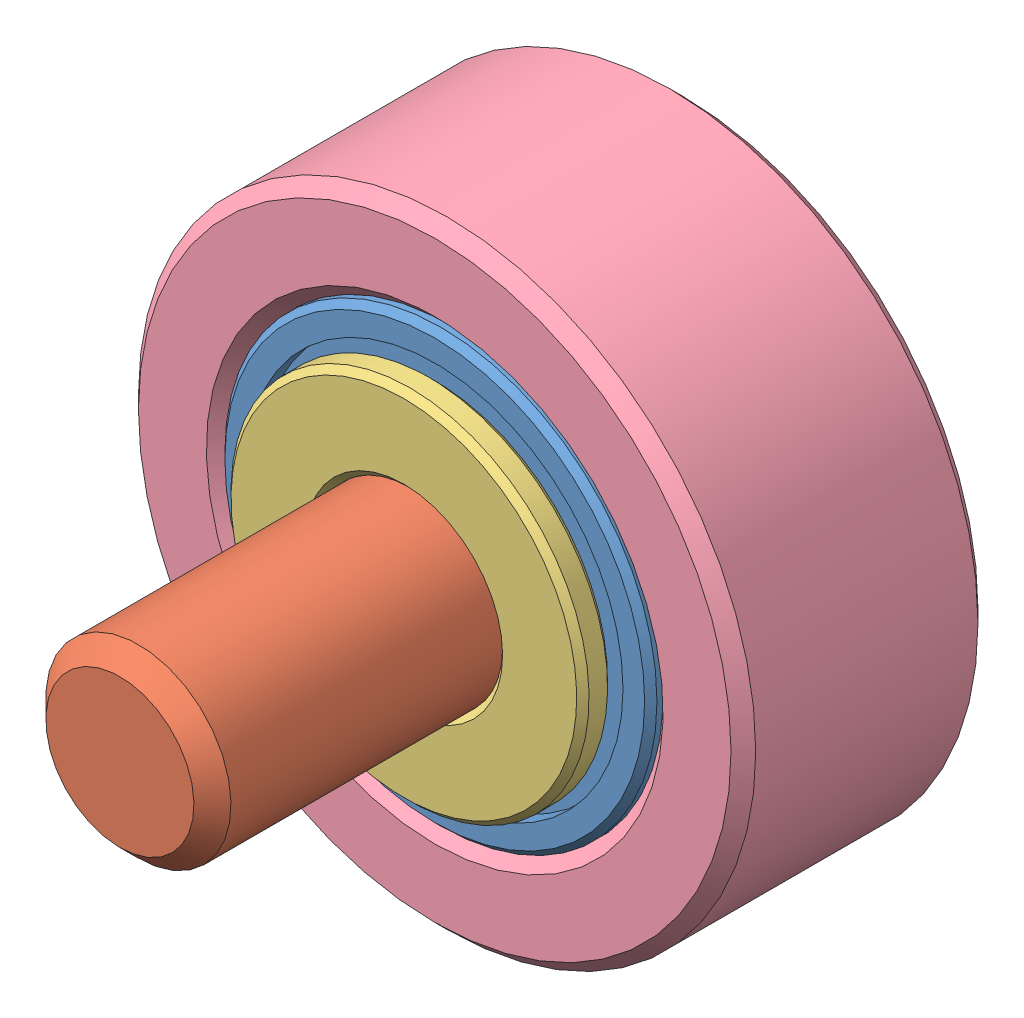
SolidWorks assembly transmission_belt_tensioner, configuration Standard. Lengths in mm.
Overall size (10 10 10).
4 component instances, 4 part files, 6 mates.
Components (placement in the parent):
- bearing_7_3_3_sbn_683_2ZVA-1: bearing_7_3_3_sbn_683_2ZVA [Standard] at origin size (7 7 3)
- fastener_fhs_m3_10-1: fastener_fhs_m3_10 [Standard] at (0 0 -3.4) x (0.710944 -0.703248 0) z (0 0 -1) size (5.8 5.8 10)
- fastener_washer_m2.5-1: fastener_washer_m2.5 [Standard] at (0 0 2) x (1 0 0) z (0 1 0) size (5.8 0.5 5.8)
- transmission_belt_tensioner_roller-1: transmission_belt_tensioner_roller [Standard] at (0 0 -0.5) x (1 0 0) z (0 1 0) size (10 4 10)
Mates (geometry in assembly coordinates):
- Deckungsgleich1: coincident aligned: line of bearing_7_3_3_sbn_683_2ZVA-1 through (0 0 -1.65) axis (0 0 1); line of fastener_fhs_m3_10-1 through (0 0 -3.9) axis (0 0 1)
- Deckungsgleich2: coincident anti-aligned: circle of bearing_7_3_3_sbn_683_2ZVA-1; cone of fastener_fhs_m3_10-1 through (0 0 -1.4) axis (0 0 1)
- Deckungsgleich3: coincident anti-aligned: line of bearing_7_3_3_sbn_683_2ZVA-1 through (0 0 -1.65) axis (0 0 1); line of fastener_washer_m2.5-1 through (0 0 2.025) axis (0 0 -1)
- Deckungsgleich4: coincident anti-aligned: plane of bearing_7_3_3_sbn_683_2ZVA-1 through (0 1.5 1.5) normal (0 0 1); plane of fastener_washer_m2.5-1 through (0 0 1.5) normal (0 0 -1)
- Deckungsgleich5: coincident anti-aligned: line of bearing_7_3_3_sbn_683_2ZVA-1 through (0 0 -1.65) axis (0 0 1); line of transmission_belt_tensioner_roller-1 through (0 0 13.9494) axis (0 0 -1)
- Deckungsgleich6: coincident anti-aligned: plane of bearing_7_3_3_sbn_683_2ZVA-1 through (0 3.05 -1.5) normal (0 0 -1); plane of transmission_belt_tensioner_roller-1 through (0 -3.5 -1.5) normal (0 0 1)
